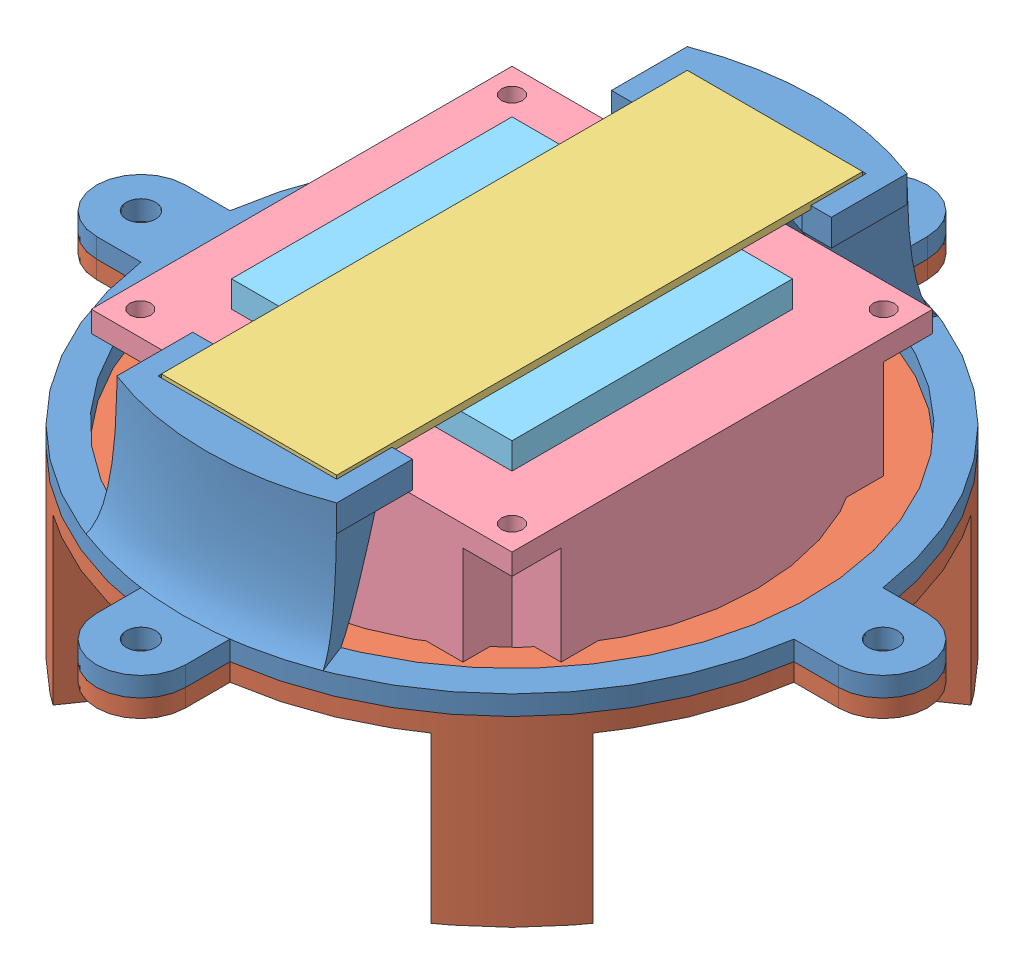
SolidWorks assembly Microscope_Slide_Stand, configuration Default. Lengths in mm.
Overall size (118.52 47.87 118.52).
6 component instances, 5 part files, 10 mates.
Components (placement in the parent):
- Slide_Holder-1: Slide_Holder [Default] at (67.4847 69.8419 73.2764) size (118.52 21.34 118.52)
- Stand_Base^Microscope_Slide_Stand-1: Stand_Base^Microscope_Slide_Stand [Default] at (67.4847 69.8419 73.2764) x (-1 0 0) z (0 -1 0) size (118.52 118.52 26.04) (virtual)
- Microscope_Slide-1: Microscope_Slide [Default] at (55.2347 90.6779 36.0264) x (0 0 1) z (-1 0 0) size (75 1 25)
- HeatSink_Peltier-1: HeatSink_Peltier [Default] at (43.828 108.9785 116.4658) size (60 28.75 60)
  - HeatSink-1: HeatSink [Default] at (-6.3433 -22.0506 -73.1894) x (1 0 0) z (0 0 -1) size (60 25 60)
  - Peltier_40mm-1: Peltier_40mm [Default] at (3.6567 -18.3006 -63.1894) x (1 0 0) z (0 -1 0) size (40 40 3.75)
Mates (geometry in assembly coordinates):
- InPlace1: in place: plane of Slide_Holder-1 through (67.4847 69.8419 73.2764) normal (0 -1 0); plane of ? through (0 69.8419 0) normal (0 -1 0); moOrthogonalPlaneRef_w of Slide_Holder-1 through (67.4847 69.8419 73.2764) normal (0 -1 0); unknown of ?; plane of Slide_Holder-1 through (67.4847 69.8419 73.2764) normal (0 -1 0); line of ? through (-55 0 69.8419) axis (0 -1 0); plane of Slide_Holder-1 through (67.4847 69.8419 73.2764) normal (0 -1 0); unknown of Stand_Base^Microscope_Slide_Stand-1
- Coincident2: coincident aligned: plane of Slide_Holder-1; plane of Stand_Base^Microscope_Slide_Stand-1
- Coincident3: coincident aligned: moOrthogonalPlaneRef_w of Slide_Holder-1 through (67.4847 69.8419 73.2764) normal (0 0 -1); plane of Stand_Base^Microscope_Slide_Stand-1
- Coincident4: coincident anti-aligned: moOrthogonalPlaneRef_w of Slide_Holder-1 through (67.4847 69.8419 73.2764) normal (1 0 0); plane of Stand_Base^Microscope_Slide_Stand-1
- Coincident2: coincident anti-aligned: plane of Slide_Holder-1 through (80.2347 90.6779 111.0264) normal (0 0 -1); plane of Microscope_Slide-1 through (55.2347 91.6779 111.0264) normal (0 0 1)
- Coincident3: coincident anti-aligned: plane of Slide_Holder-1 through (80.2347 90.6779 111.0264) normal (-1 0 0); plane of Microscope_Slide-1 through (80.2347 91.6779 36.0264) normal (1 0 0)
- Coincident4: coincident anti-aligned: plane of Slide_Holder-1 through (67.4847 90.6779 73.2764) normal (0 1 0); plane of Microscope_Slide-1 through (55.2347 90.6779 36.0264) normal (0 -1 0)
- Coincident5: coincident anti-aligned: plane of Microscope_Slide-1 through (55.2347 90.6779 36.0264) normal (0 -1 0); plane of HeatSink_Peltier-1/Peltier_40mm-1 through (47.4847 90.6779 53.2764) normal (0 1 0)
- Parallel2: parallel aligned: plane of Microscope_Slide-1 through (80.2347 91.6779 36.0264) normal (1 0 0); plane of HeatSink_Peltier-1/HeatSink-1 through (97.4847 83.9279 43.2764) normal (1 0 0)
- Concentric1: concentric anti-aligned: circle of Stand_Base^Microscope_Slide_Stand-1; circle of HeatSink_Peltier-1/Peltier_40mm-1
